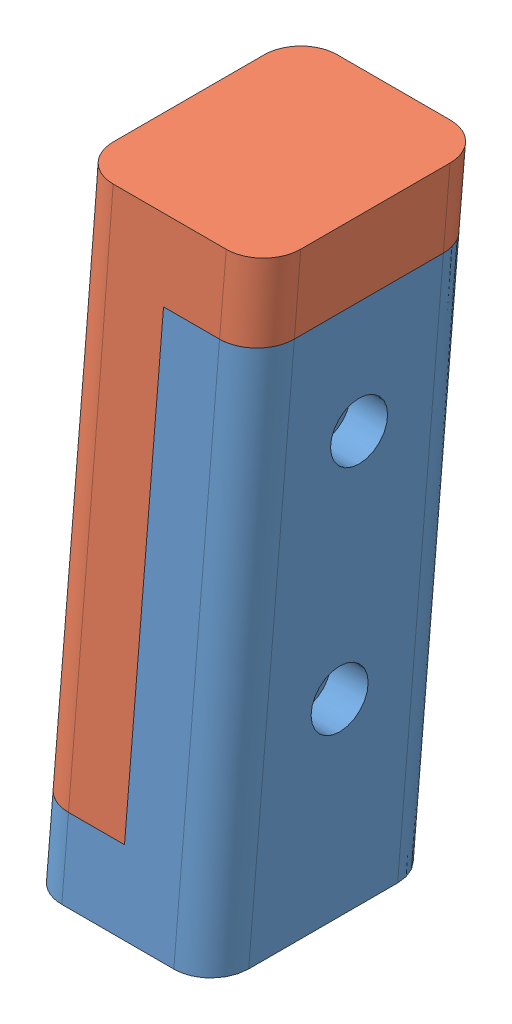
SolidWorks assembly Assem1, configuration Default. Lengths in mm.
Overall size (25.57 80.85 37.28).
2 component instances, 2 part files, 1 mates.
Components (placement in the parent):
- bottom_section_test-1: bottom_section_test [Default] at (1.736 -130.6486 138.5517) size (25 70 36.12)
- top_section_test-1: top_section_test [Default] at (14.236 69.3514 138.5517) x (-1 0 0) z (0 0 -1) size (25.57 71.48 36.67)
Mates (geometry in assembly coordinates):
- Coincident1: coincident: circle of bottom_section_test-1; circle of top_section_test-1
